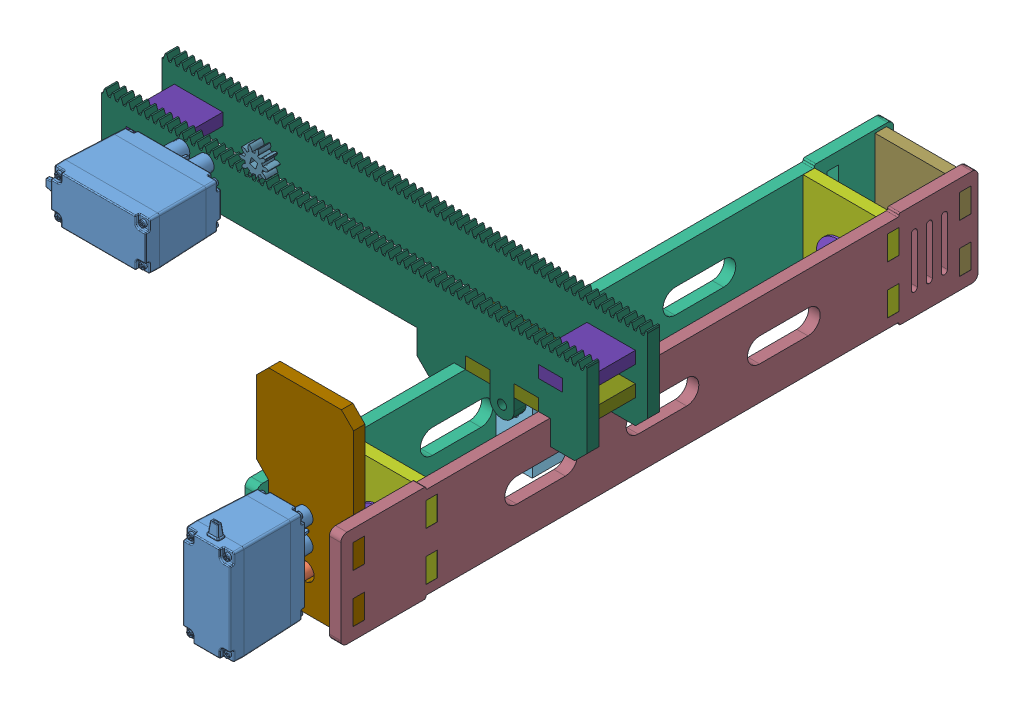
SolidWorks assembly Assem6, configuration Default. Lengths in mm.
Overall size (254 101.6 385.81).
24 component instances, 17 part files, 4 mates.
Components (placement in the parent):
- Axis 1-1: Axis 1 [Default] at (-23.8117 64.0312 -37.9094) x (0 1 0) z (0 0 1) size (101.6 50.8 385.81)
  - 276-2177-1: 276-2177 [Default] at (-34.5901 9.5753 240.5294) x (-1 0 0) z (0 1 0) size (56.4 55.81 25)
  - Square Shaft Adapter-1: Square Shaft Adapter [Default] at (-60.2901 9.5753 206.0294) x (-0.971099 -0.238678 0) z (0 0 -1) size (6.35 6.35 31.75)
  - 95475A656-1: 95475A656 [95475A656] at (-60.2901 9.5753 28.2294) x (0.981691 0.190478 0) z (0 0 1) size (11 9.67 270.12)
  - Threaded Rod Shaft Coupler-1: Threaded Rod Shaft Coupler [Default] at (-60.2901 9.5753 161.5794) x (1 0 0) z (0 -1 0) size (19.05 25.4 19.05)
  - Adapter-1: Adapter [Default] at (-68.2276 9.5753 73.8865) x (0 -1 0) z (0 0 1) size (19.05 38.1 25.4)
  - Side Plate-1: Side Plate [Default] at (-28.5401 28.6253 -102.4552) x (0 0 -1) z (0 1 0) size (333.38 50.8 5.99)
  - Bearing Block-1: Bearing Block [Default] at (-60.2901 9.5753 -83.7608) x (0 -1 0) z (0 0 -1) size (50.09 47.62 5.99)
  - Bearing-1: Bearing [Default] at (-60.2901 9.5753 -89.7552) size (22.23 22.23 7.11)
  - Bearing Block-2: Bearing Block [Default] at (-60.2901 9.5753 151.9004) x (0 1 0) z (0 0 1) size (50.09 47.62 5.99)
  - Bearing-2: Bearing [Default] at (-60.2901 9.5753 151.9004) size (22.23 22.23 7.11)
  - Motor Block-1: Motor Block [Default] at (-28.5401 28.6253 190.0004) x (0 1 0) z (0 0 1) size (50.8 101.6 5.99)
  - Position Sensor-1: Position Sensor [Default] at (-60.2901 9.5753 -138.2676) x (0.975862 0.218387 0) z (0.218387 -0.975862 0) size (19.05 33.15 19.05)
  - Position Sensor Adapter-1: Position Sensor Adapter [Default] at (-60.2901 9.5753 -94.0081) x (0.787081 0.616849 0) z (-0.616849 0.787081 0) size (12.7 17.46 12.7)
  - Sensor Block-1: Sensor Block [Default] at (-28.5401 28.6253 -127.3456) x (0 1 0) z (0 0 1) size (50.09 47.62 5.99)
  - Side Plate 2-2: Side Plate 2 [Default] at (-28.5401 -15.5523 -102.4552) x (0 0 -1) z (0 1 0) size (333.38 50.8 5.99)
- Axis 2-1: Axis 2 [Default] at (-187.6142 15.7796 74.2259) x (0 0 1) z (-1 0 0) size (105.18 63.25 254)
  - Spur Gear-1: Spur Gear [Inch - Spur gear 20DP 10T 20PA 0.25"FW ---S10N3.0H2.0L0.1875N] at (-25.5488 56.17 -24.2712) x (1 0 0) z (0 0.958122 -0.28636) size (6.35 114.29 15.24)
  - Rack-1: Rack [Inch - Rack-spur - rectangular 20DP 20PA 0.25"FW 1"PH 10L---SAll] at (-19.1988 24.474 55.3228) x (0 0 -1) z (1 0 0) size (254 45.72 6.35)
  - 276-2177-1: 276-2177 [Default] at (40.8761 56.17 1.4288) x (0 0 -1) z (0 -1 0) size (56.4 55.81 25)
  - Adapter Plate-1: Adapter Plate [Default] at (-38.2488 18.124 -147.8772) x (0 0 1) z (-1 0 0) size (76.2 6.35 38.1)
  - Rack-2: Rack [Inch - Rack-spur - rectangular 20DP 20PA 0.25"FW 1"PH 10L---SAll] at (-50.9488 24.474 55.3228) x (0 0 -1) z (1 0 0) size (254 45.72 6.35)
  - Rack Bridge-3: Rack Bridge [Default] at (-50.9488 33.237 48.9728) x (0 0 1) z (0 1 0) size (25.4 38.1 6.35)
  - Rack Bridge-4: Rack Bridge [Default] at (-50.9488 33.237 -166.9272) x (0 0 1) z (0 1 0) size (25.4 38.1 6.35)
Mates (geometry in assembly coordinates):
- Parallel3: parallel aligned: plane of Axis 1-1/Side Plate-1 through (-52.437 34.0036 119.9855) normal (0 1 0); plane of assembly through (0 0 0) normal (0 1 0)
- Concentric1: concentric aligned: cylinder of Axis 1-1/Adapter-1 through (-33.387 -4.1974 35.9771) axis (0 1 0) radius 2.3495; circle of Axis 2-1/Adapter Plate-1
- Coincident4: coincident anti-aligned: plane of Axis 1-1/Adapter-1 through (-33.387 33.9036 35.9771) normal (0 1 0); plane of Axis 2-1/Adapter Plate-1 through (-39.737 33.9036 35.9771) normal (0 -1 0)
- Coincident5: coincident anti-aligned: plane of Axis 1-1/Adapter-1 through (-42.912 33.9036 48.6771) normal (0 0 1); plane of Axis 2-1/Rack-1 through (-242.937 66.9236 48.6771) normal (0 0 -1)
